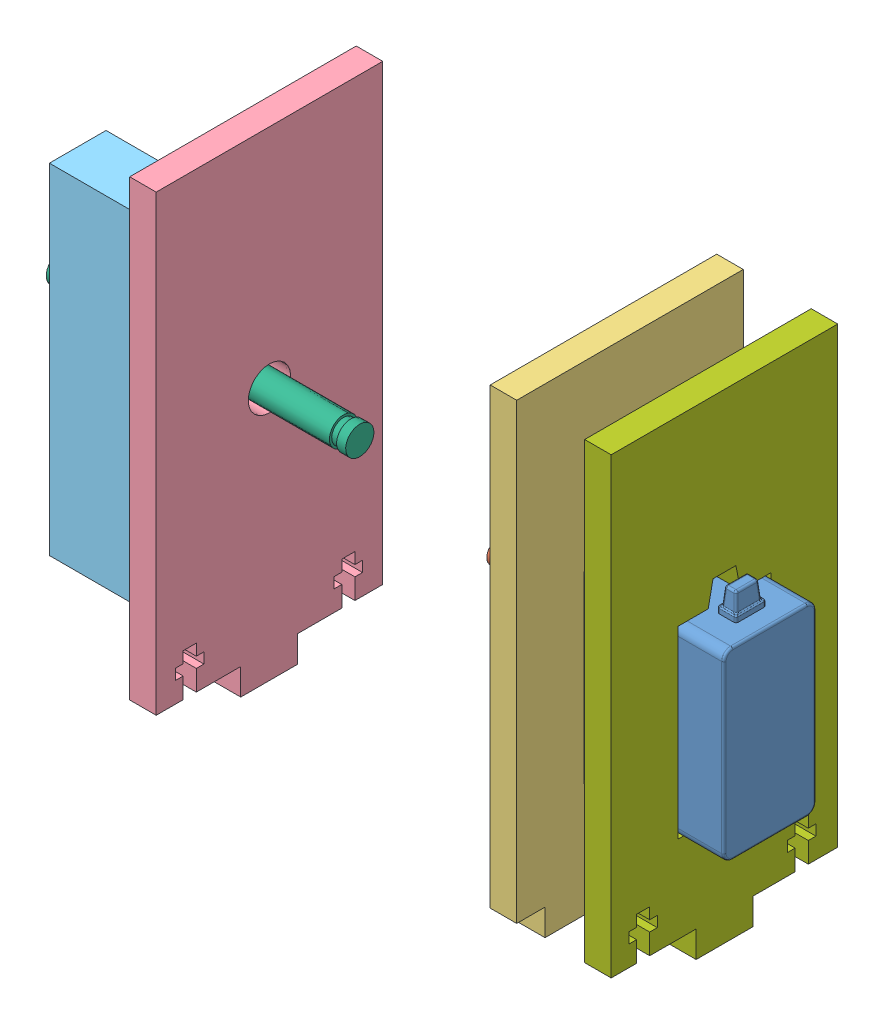
SolidWorks assembly SupportAssem, configuration Default. Lengths in mm.
Overall size (159.12 107.54 50.8).
7 component instances, 7 part files, 17 mates.
Components (placement in the parent):
- Servo SpringRC Rev1-1: Servo SpringRC Rev1 [Default] at (-74.825 -21.7734 20.8739) size (46.2 55.75 20.86)
- hs-422_horn_2wings_sws-4: hs-422_horn_2wings_sws [Default] at (-80.825 9.5266 31.2239) x (0 0.883679 -0.468092) z (0 0.468092 0.883679) size (9.1 5 34)
- Support1-1: Support1 [Default] at (-71.9686 -41.2734 56.6239) x (0 0 -1) z (1 0 0) size (50.8 107.54 5.94)
- Support2-1: Support2 [Default] at (-152.8046 -41.2734 5.8239) x (0 1 0) z (1 0 0) size (107.54 50.8 5.94)
- Scoop shaft support-1: Scoop shaft support [Default] at (-151.7578 -41.2734 12.1739) x (-1 0 0) z (0 0 -1) size (38.1 76.2 25.4)
- 2 inch shaft-1: 2 inch shaft [Default] at (-189.8578 9.5266 31.2239) x (0 0.432014 -0.901867) z (1 0 0) size (6.35 6.35 67.13)
- Support3-1: Support3 [Default] at (-50.785 -41.2734 5.8239) x (0 0 -1) z (1 0 0) size (50.8 107.54 5.94)
Mates (geometry in assembly coordinates):
- Concentric2: concentric: cylinder of Servo SpringRC Rev1-1 through (-80.825 9.5266 31.2239) axis (1 0 0) radius 3; cylinder of hs-422_horn_2wings_sws-4 through (-78.325 9.5266 31.2239) axis (-1 0 0) radius 2.5
- Coincident2: coincident: plane of Servo SpringRC Rev1-1 through (-80.825 9.5266 31.2239) normal (-1 0 0); plane of hs-422_horn_2wings_sws-4 through (-80.825 2.7393 18.4105) normal (1 0 0)
- Coincident5: coincident: plane of Servo SpringRC Rev1-1 through (-66.025 26.7516 20.8739) normal (-1 0 0); plane of Support1-1 through (-66.025 -41.2734 56.6239) normal (1 0 0)
- Parallel3: parallel: plane of Support1-1 through (-71.9686 -41.2734 56.6239) normal (-1 0 0); plane of Support2-1 through (-146.861 -41.2734 5.8239) normal (1 0 0)
- Parallel4: parallel: plane of Support1-1 through (-66.025 60.3266 56.6239) normal (0 1 0); plane of Support2-1 through (-146.861 60.3266 5.8239) normal (0 1 0)
- Concentric6: concentric: circle of Support2-1; circle of Scoop shaft support-1
- Coincident21: coincident: plane of Support2-1 through (-146.861 -41.2734 5.8239) normal (0 -1 0); plane of Scoop shaft support-1 through (-189.8578 -41.2734 12.1739) normal (0 -1 0)
- Concentric7: concentric: circle of Support2-1; circle of 2 inch shaft-1
- Concentric8: concentric: circle of hs-422_horn_2wings_sws-4; circle of Support2-1
- Coincident24: coincident: plane of Support2-1 through (-146.861 -41.2734 5.8239) normal (0 -1 0); plane of Support1-1 through (-66.025 -41.2734 56.6239) normal (0 -1 0)
- Parallel7: parallel: cylinder of Servo SpringRC Rev1-1 through (-74.325 19.5266 41.0739) axis (0 -1 0) radius 0.5; line of Support1-1 through (-71.9686 60.3266 56.6239) axis (0 -1 0)
- Coincident28: coincident: plane of Scoop shaft support-1 through (-189.8578 -41.2734 12.1739) normal (-1 0 0); plane of 2 inch shaft-1 through (-189.8578 9.5266 31.2239) normal (-1 0 0)
- Coincident29: coincident: plane of Support1-1 through (-66.025 -41.2734 5.8239) normal (0 0 -1); plane of Support2-1 through (-146.861 -41.2734 5.8239) normal (0 0 -1)
- Coincident30: coincident: plane of Support1-1 through (-66.025 -41.2734 56.6239) normal (0 0 1); plane of Support2-1 through (-146.861 -41.2734 56.6239) normal (0 0 1)
- Coincident31: coincident: plane of Support1-1 through (-66.025 -41.2734 56.6239) normal (0 -1 0); plane of Support3-1 through (-44.8414 -41.2734 37.5739) normal (0 -1 0)
- Distance1: distance = 15.24 mm: plane of Support1-1 through (-66.025 -41.2734 56.6239) normal (1 0 0); plane of Support3-1 through (-50.785 -41.2734 5.8239) normal (-1 0 0)
- Coincident36: coincident: plane of Support1-1 through (-66.025 -41.2734 56.6239) normal (0 0 1); plane of Support3-1 through (-44.8414 -41.2734 56.6239) normal (0 0 1)
